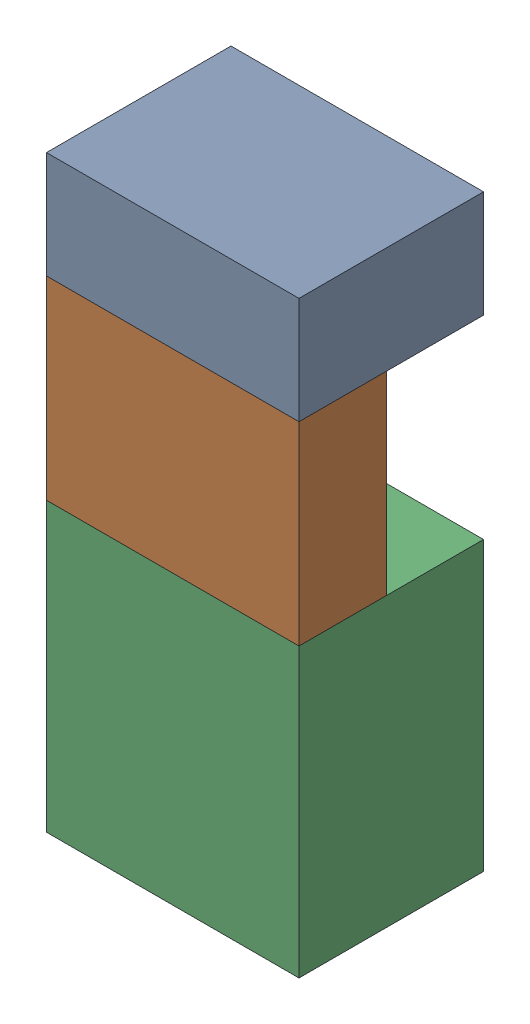
SolidWorks assembly SUP_K7, configuration Default. Lengths in mm.
Overall size (13 30.3 9.5).
6 component instances, 3 part files, 0 mates.
Components (placement in the parent):
- 1151724928-1: 1151724928 [Default] at (98.425 41.975 0) size (13 5.5 9.5)
  - Extruded_2-1: Extruded_2 [Default] at origin size (13 5.5 9.5)
- 1151725064-1: 1151725064 [Default] at (98.425 34.225 5) size (13 10 4.5)
  - Extruded_3-1: Extruded_3 [Default] at origin size (13 10 4.5)
- 1151724792-1: 1151724792 [Default] at (98.425 21.825 0) size (13 14.8 9.5)
  - Extruded_4-1: Extruded_4 [Default] at origin size (13 14.8 9.5)
